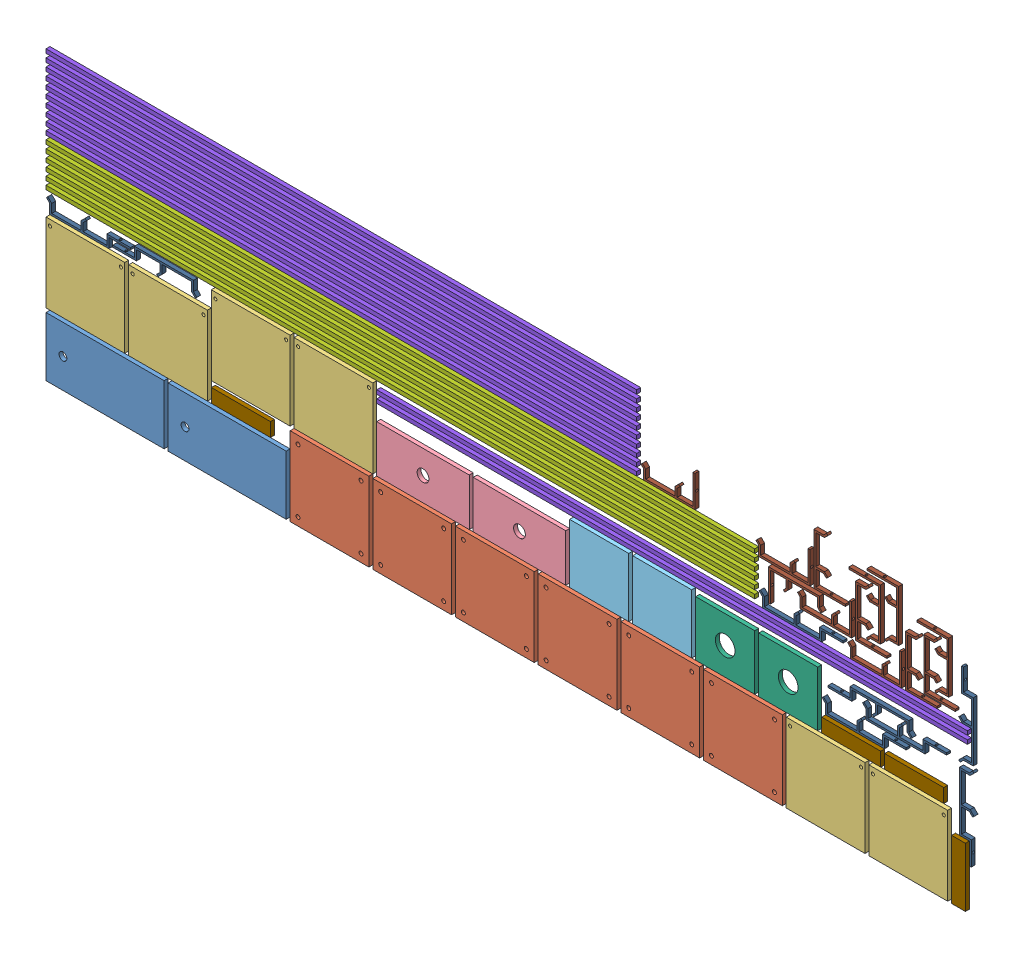
SolidWorks assembly Nesting(10mm), configuration Layout1[Steel_10mm_Qnty1]. Lengths in mm.
Overall size (2357.02 730 10).
62 component instances, 11 part files, 0 mates.
Components (placement in the parent):
- Z_Top_Plate-1: Z_Top_Plate [Default] at (170 95 0) x (0 1 0) z (0 0 -1) size (150 300 10)
- Z_Top_Plate-2: Z_Top_Plate [Default] at (480 95 0) x (0 1 0) z (0 0 -1) size (150 300 10)
- Base_Plate_X-1: Base_Plate_X [Default] at (740 120 0) x (1 0 0) z (0 1 0) size (200 10 200)
- Base_Plate_X-2: Base_Plate_X [Default] at (950 120 0) x (1 0 0) z (0 1 0) size (200 10 200)
- Base_Plate_X-3: Base_Plate_X [Default] at (1160 120 0) x (1 0 0) z (0 1 0) size (200 10 200)
- Base_Plate_X-4: Base_Plate_X [Default] at (1370 120 0) x (1 0 0) z (0 1 0) size (200 10 200)
- Base_Plate_X-5: Base_Plate_X [Default] at (1580 120 0) x (1 0 0) z (0 1 0) size (200 10 200)
- Base_Plate_X-6: Base_Plate_X [Default] at (1790 120 0) x (1 0 0) z (0 1 0) size (200 10 200)
- Top_Plate_X-1: Top_Plate_X [Default] at (2000 120 0) x (1 0 0) z (0 1 0) size (200 10 200)
- Top_Plate_X-2: Top_Plate_X [Default] at (2210 120 0) x (1 0 0) z (0 1 0) size (200 10 200)
- Top_Plate_X-3: Top_Plate_X [Default] at (120 280 0) x (1 0 0) z (0 1 0) size (200 10 200)
- Top_Plate_X-4: Top_Plate_X [Default] at (330 280 0) x (1 0 0) z (0 1 0) size (200 10 200)
- Top_Plate_X-5: Top_Plate_X [Default] at (540 330 0) x (1 0 0) z (0 1 0) size (200 10 200)
- Top_Plate_X-6: Top_Plate_X [Default] at (750 330 0) x (1 0 0) z (0 1 0) size (200 10 200)
- Motor Extension Plate-1: Motor Extension Plate [Default] at (977.5 290 0) x (1 0 0) z (0 0 -1) size (235 120 10)
- Motor Extension Plate-2: Motor Extension Plate [Default] at (1222.5 290 0) x (1 0 0) z (0 0 -1) size (235 120 10)
- Horizontal_Plate-1: Horizontal_Plate [Default] at (1425 305 0) x (1 0 0) z (0 1 0) size (150 10 150)
- Horizontal_Plate-2: Horizontal_Plate [Default] at (1585 305 0) x (1 0 0) z (0 1 0) size (150 10 150)
- Vertical_Plate-1: Vertical_Plate [Default] at (1745 300 0) x (1 0 0) z (0 0 -1) size (150 140 10)
- Vertical_Plate-2: Vertical_Plate [Default] at (1905 300 0) x (1 0 0) z (0 0 -1) size (150 140 10)
- Railings_y-1: Railings_y [Default] at (20 445 -5) x (0 0 -1) z (1 0 0) size (10 10 1800)
- Railings_y-2: Railings_y [Default] at (20 465 -5) x (0 0 -1) z (1 0 0) size (10 10 1800)
- Railings_y-3: Railings_y [Default] at (20 485 -5) x (0 0 -1) z (1 0 0) size (10 10 1800)
- Railings_y-4: Railings_y [Default] at (20 505 -5) x (0 0 -1) z (1 0 0) size (10 10 1800)
- Railings_y-5: Railings_y [Default] at (20 525 -5) x (0 0 -1) z (1 0 0) size (10 10 1800)
- Railings_y-6: Railings_y [Default] at (20 545 -5) x (0 0 -1) z (1 0 0) size (10 10 1800)
- X_Railings-1: X_Railings [Default] at (2360 395 -5) x (0 0 -1) z (0 1 0) size (10 1500 10)
- X_Railings-2: X_Railings [Default] at (2360 415 -5) x (0 0 -1) z (0 1 0) size (10 1500 10)
- X_Railings-3: X_Railings [Default] at (1520 565 -5) x (0 0 -1) z (0 1 0) size (10 1500 10)
- X_Railings-4: X_Railings [Default] at (1520 585 -5) x (0 0 -1) z (0 1 0) size (10 1500 10)
- X_Railings-5: X_Railings [Default] at (1520 605 -5) x (0 0 -1) z (0 1 0) size (10 1500 10)
- X_Railings-6: X_Railings [Default] at (1520 625 -5) x (0 0 -1) z (0 1 0) size (10 1500 10)
- X_Railings-7: X_Railings [Default] at (1520 645 -5) x (0 0 -1) z (0 1 0) size (10 1500 10)
- X_Railings-8: X_Railings [Default] at (1520 665 -5) x (0 0 -1) z (0 1 0) size (10 1500 10)
- X_Railings-9: X_Railings [Default] at (1520 685 -5) x (0 0 -1) z (0 1 0) size (10 1500 10)
- X_Railings-10: X_Railings [Default] at (1520 705 -5) x (0 0 -1) z (0 1 0) size (10 1500 10)
- X_Railings-11: X_Railings [Default] at (1520 725 -5) x (0 0 -1) z (0 1 0) size (10 1500 10)
- X_Railings-12: X_Railings [Default] at (1520 745 -5) x (0 0 -1) z (0 1 0) size (10 1500 10)
- Lower_Section-1: Lower_Section [Default] at (2355 20 0) x (0 0 -1) z (1 0 0) size (10 150 35)
- Lower_Section-2: Lower_Section [Default] at (590 215 0) x (0 0 -1) z (0 1 0) size (10 150 35)
- Lower_Section-3: Lower_Section [Default] at (2140 265 0) x (0 0 -1) z (0 1 0) size (10 150 35)
- Lower_Section-4: Lower_Section [Default] at (2300 265 0) x (0 0 -1) z (0 1 0) size (10 150 35)
- Drag_Chain_Bracket_Y-1: Drag_Chain_Bracket_Y [Default] at (2356.3648 287.5 -10) x (0 -1 0) z (0 0 1) size (213.49 37.02 10)
- Drag_Chain_Bracket_Y-2: Drag_Chain_Bracket_Y [Default] at (2042.0208 291.3648 -10) size (213.49 37.02 10)
- Drag_Chain_Bracket_Y-3: Drag_Chain_Bracket_Y [Default] at (2144.598 331.3648 -10) size (213.49 37.02 10)
- Drag_Chain_Bracket_Y-4: Drag_Chain_Bracket_Y [Default] at (2169.1188 351.6916 -10) x (-1 0 0) z (0 0 1) size (213.49 37.02 10)
- Drag_Chain_Bracket_Y-5: Drag_Chain_Bracket_Y [Default] at (72.0208 406.3648 -10) size (213.49 37.02 10)
- Drag_Chain_Bracket_Y-6: Drag_Chain_Bracket_Y [Default] at (352.0208 411.6916 -10) x (-1 0 0) z (0 0 1) size (213.49 37.02 10)
- Drag_Chain_Bracket_Y-7: Drag_Chain_Bracket_Y [Default] at (2358.6352 392.5 -10) x (0 1 0) z (0 0 1) size (213.49 37.02 10)
- Drag_Chain_Bracket_Y-8: Drag_Chain_Bracket_Y [Default] at (1882.0208 446.3648 -10) size (213.49 37.02 10)
- Drag_Chain_Bracket-1: Drag_Chain_Bracket [Default] at (2124.0921 463.0581 -10) size (137.07 80 10)
- Drag_Chain_Bracket-2: Drag_Chain_Bracket [Default] at (2235.6861 498.5359 -10) x (0 -1 0) z (0 0 1) size (137.07 80 10)
- Drag_Chain_Bracket-3: Drag_Chain_Bracket [Default] at (1996.9641 509.7004 -10) size (137.07 80 10)
- Drag_Chain_Bracket-4: Drag_Chain_Bracket [Default] at (2282.3286 515.3835 -10) x (0 -1 0) z (0 0 1) size (137.07 80 10)
- Drag_Chain_Bracket-5: Drag_Chain_Bracket [Default] at (1923.0567 495.2265 -10) x (-1 0 0) z (0 0 1) size (137.07 80 10)
- Drag_Chain_Bracket-6: Drag_Chain_Bracket [Default] at (2108.5581 545.1783 -10) x (0 -1 0) z (0 0 1) size (137.07 80 10)
- Drag_Chain_Bracket-7: Drag_Chain_Bracket [Default] at (2279.6558 531.4189 -10) x (0 1 0) z (0 0 1) size (137.07 80 10)
- Drag_Chain_Bracket-8: Drag_Chain_Bracket [Default] at (1891.4643 571.3427 -10) size (137.07 80 10)
- Drag_Chain_Bracket-9: Drag_Chain_Bracket [Default] at (2105.8854 561.2137 -10) x (0 1 0) z (0 0 1) size (137.07 80 10)
- Drag_Chain_Bracket-10: Drag_Chain_Bracket [Default] at (1599.5713 593.0581 -10) size (137.07 80 10)
- Drag_Chain_Bracket-11: Drag_Chain_Bracket [Default] at (2003.0583 606.8205 -10) x (0 -1 0) z (0 0 1) size (137.07 80 10)
- Drag_Chain_Bracket-12: Drag_Chain_Bracket [Default] at (2152.5278 581.4643 -10) x (0 1 0) z (0 0 1) size (137.07 80 10)
